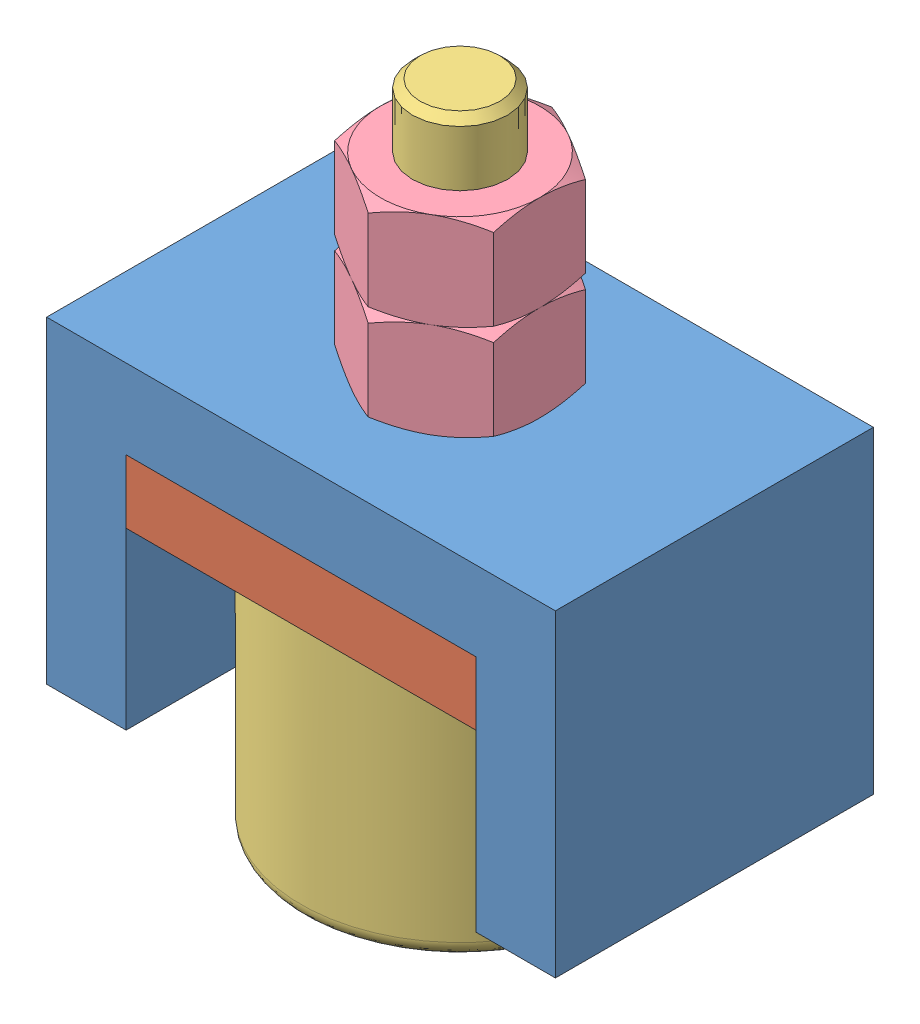
SolidWorks assembly Amortisseur, configuration Défaut. Lengths in mm.
Overall size (32 45 20).
5 component instances, 4 part files, 11 mates.
Components (placement in the parent):
- AmortisseurSupportBille-1: AmortisseurSupportBille [Défaut] at origin size (32 20 20)
- AmortisseurMousse-1: AmortisseurMousse [Défaut] at (0 11 0) size (22 4 20)
- AmortisseurBille-2: AmortisseurBille [Défaut] at (0 13.5 0) size (20 45 20)
- H-M6-1: H-M6 [Défaut] at (0 26 0) x (-1 0 0) z (0 -1 0) size (10 11.55 6)
- H-M6-2: H-M6 [Défaut] at (0 32 0) x (-1 0 0) z (0 -1 0) size (10 11.55 6)
Mates (geometry in assembly coordinates):
- Coaxiale1: concentric anti-aligned: cylinder of AmortisseurSupportBille-1 through (0 0 0) axis (0 1 0) radius 3; cylinder of AmortisseurMousse-1 through (0 15 0) axis (0 -1 0) radius 3.25
- Parallèle1: parallel aligned: plane of AmortisseurSupportBille-1 through (-16 0 10) normal (0 0 1); plane of AmortisseurMousse-1 through (-11 15 10) normal (0 0 1)
- Coïncidente2: coincident anti-aligned: plane of AmortisseurSupportBille-1 through (11 15 10) normal (0 -1 0); plane of AmortisseurMousse-1 through (-11 15 10) normal (0 1 0)
- Coaxiale2: concentric aligned: cylinder of AmortisseurSupportBille-1 through (0 0 0) axis (0 1 0) radius 3; cylinder of AmortisseurBille-2 through (0 36 0) axis (0 1 0) radius 3
- Coïncidente3: coincident anti-aligned: plane of AmortisseurMousse-1 through (-11 11 10) normal (0 -1 0); plane of AmortisseurBille-2 through (-10 11 0) normal (0 1 0)
- Coaxiale3: concentric anti-aligned: cylinder of AmortisseurBille-2 through (0 36 0) axis (0 1 0) radius 3; cylinder of H-M6-1 through (0 26.001 0) axis (0 -1 0) radius 2.5
- Coïncidente4: coincident anti-aligned: plane of AmortisseurSupportBille-1 through (-16 20 10) normal (0 1 0); plane of H-M6-1 through (0 20 0) normal (0 -1 0)
- Coïncidente5: coincident anti-aligned: plane of H-M6-1; plane of assembly
- Coaxiale4: concentric anti-aligned: cylinder of AmortisseurBille-2 through (0 36 0) axis (0 1 0) radius 3; cylinder of H-M6-2 through (0 32.001 0) axis (0 -1 0) radius 2.5
- Coïncidente6: coincident anti-aligned: plane of H-M6-1 through (0 26 0) normal (0 1 0); plane of H-M6-2 through (0 26 0) normal (0 -1 0)
- Coïncidente7: coincident anti-aligned: plane of H-M6-2; plane of assembly
